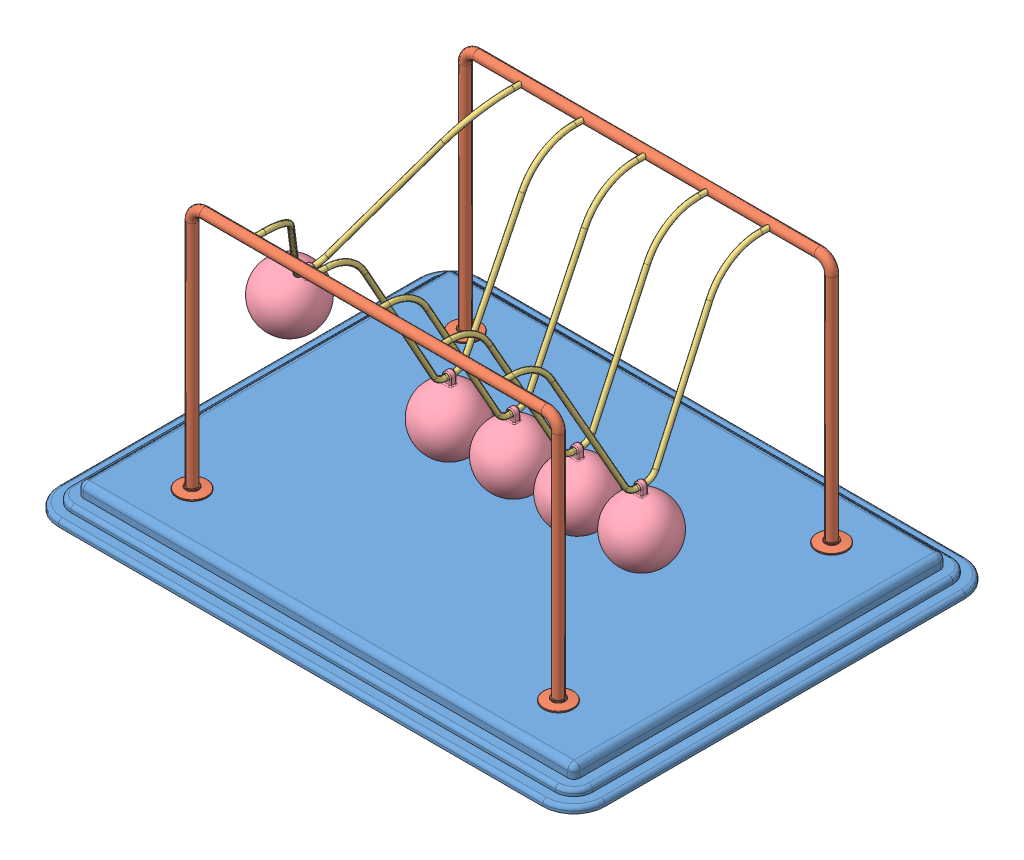
SolidWorks assembly Newtons Cradle NewtonsCradle 0250, configuration Default. Lengths in mm.
Overall size (440 222 340).
13 component instances, 4 part files, 34 mates.
Components (placement in the parent):
- Base 202.59319286872-1: Base 202.59319286872 [Default] at (-16.2968 -4.1587 11.425) size (440 20 340)
- frame NewtonsCradle 0250-1: frame NewtonsCradle 0250 [Default] at (-16.2968 144.4547 -98.575) size (319 202 24)
- frame NewtonsCradle 0250-2: frame NewtonsCradle 0250 [Default] at (-16.2968 144.4547 121.425) x (-1 0 0) z (0 0 -1) size (319 202 24)
- Hanging thing NewtonsCradle 0250-1: Hanging thing NewtonsCradle 0250 [Default] at (-157.6326 134.1825 11.425) x (0 0 1) z (-0.859985 0.510319 0) size (220 129 4)
- Hanging thing NewtonsCradle 0250-2: Hanging thing NewtonsCradle 0250 [Default] at (-66.576 122.8418 11.425) x (0 0 1) z (-0.999994 0.003446 0) size (220 129 4)
- Hanging thing NewtonsCradle 0250-3: Hanging thing NewtonsCradle 0250 [Default] at (-15.6923 122.8436 11.425) x (0 0 1) z (-0.999972 -0.007464 0) size (220 129 4)
- Hanging thing NewtonsCradle 0250-4: Hanging thing NewtonsCradle 0250 [Default] at (35.2213 122.8555 11.425) x (0 0 1) z (-0.999824 -0.018742 0) size (220 129 4)
- Hanging thing NewtonsCradle 0250-5: Hanging thing NewtonsCradle 0250 [Default] at (86.0287 122.8747 11.425) x (0 0 1) z (-0.999588 -0.028711 0) size (220 129 4)
- Sphere NewtonsCradle 0250-1: Sphere NewtonsCradle 0250 [Default] at (-195.3962 70.5436 11.425) x (0.859985 -0.510319 0) z (0 0 1) size (50 58.5 50)
- Sphere NewtonsCradle 0250-2: Sphere NewtonsCradle 0250 [Default] at (88.1533 48.9052 11.425) x (0.999588 0.028711 0) z (0 0 1) size (50 58.5 50)
- Sphere NewtonsCradle 0250-3: Sphere NewtonsCradle 0250 [Default] at (-15.14 48.8456 11.425) x (0.999972 0.007464 0) z (0 0 1) size (50 58.5 50)
- Sphere NewtonsCradle 0250-4: Sphere NewtonsCradle 0250 [Default] at (36.6081 48.8685 11.425) x (0.999824 0.018742 0) z (0 0 1) size (50 58.5 50)
- Sphere NewtonsCradle 0250-5: Sphere NewtonsCradle 0250 [Default] at (-66.831 48.8422 11.425) x (0.999994 -0.003446 0) z (0 0 1) size (50 58.5 50)
Mates (geometry in assembly coordinates):
- Coincident1: coincident anti-aligned: plane of Base-1 through (-211.2968 5.8413 156.425) normal (0 1 0); plane of frame-2 through (-175.7968 5.8413 121.425) normal (0 -1 0)
- Coincident2: coincident anti-aligned: plane of Base-1 through (-211.2968 5.8413 156.425) normal (0 1 0); plane of frame-1 through (143.2032 5.8413 -98.575) normal (0 -1 0)
- Concentric1: concentric anti-aligned: cylinder of frame-1 through (-116.2968 203.8413 -94.575) axis (0 0 -1) radius 2; cylinder of frame-2 through (-116.2968 203.8413 117.425) axis (0 0 1) radius 2
- Concentric2: concentric anti-aligned: cylinder of frame-1 through (83.7032 203.8413 -94.575) axis (0 0 -1) radius 2; cylinder of frame-2 through (83.7032 203.8413 117.425) axis (0 0 1) radius 2
- Distance1: distance = 60 mm: plane of frame-1 through (-16.2968 144.4547 -98.575) normal (0 0 1); line of Base-1 through (-211.2968 -12.1587 -158.575) axis (1 0 0)
- Distance2: distance = 60 mm: line of Base-1 through (178.7032 -12.1587 181.425) axis (-1 0 0); plane of frame-2 through (-16.2968 144.4547 121.425) normal (0 0 -1)
- Distance3: distance = 220 mm: plane of frame-2 through (-16.2968 144.4547 121.425) normal (-1 0 0); line of Base-1 through (-236.2968 -12.1587 156.425) axis (0 0 -1)
- Concentric3: concentric anti-aligned: cylinder of frame-1 through (-116.2968 203.8413 -94.575) axis (0 0 -1) radius 2; cylinder of Hanging thing-1 through (-116.2968 203.8413 111.425) axis (0 0 1) radius 2
- Concentric4: concentric anti-aligned: cylinder of frame-1 through (-116.2968 203.8413 -94.575) axis (0 0 -1) radius 2; cylinder of Hanging thing-1 through (-116.2968 203.8413 -98.575) axis (0 0 1) radius 2
- Concentric5: concentric aligned: cylinder of frame-2 through (-66.2968 203.8413 117.425) axis (0 0 1) radius 2; cylinder of Hanging thing-2 through (-66.2968 203.8413 111.425) axis (0 0 1) radius 2
- Concentric6: concentric aligned: cylinder of frame-2 through (-16.2968 203.8413 117.425) axis (0 0 1) radius 2; cylinder of Hanging thing-3 through (-16.2968 203.8413 111.425) axis (0 0 1) radius 2
- Concentric7: concentric aligned: cylinder of frame-2 through (33.7032 203.8413 117.425) axis (0 0 1) radius 2; cylinder of Hanging thing-4 through (33.7032 203.8413 111.425) axis (0 0 1) radius 2
- Concentric8: concentric aligned: cylinder of frame-2 through (83.7032 203.8413 117.425) axis (0 0 1) radius 2; cylinder of Hanging thing-5 through (83.7032 203.8413 111.425) axis (0 0 1) radius 2
- Coincident5: coincident anti-aligned: plane of frame-2 through (83.7032 203.8413 121.425) normal (0 0 -1); plane of Hanging thing-5 through (83.7032 203.8413 121.425) normal (0 0 1)
- Coincident6: coincident anti-aligned: plane of frame-2 through (33.7032 203.8413 121.425) normal (0 0 -1); plane of Hanging thing-4 through (33.7032 203.8413 121.425) normal (0 0 1)
- Coincident7: coincident anti-aligned: plane of frame-2 through (-16.2968 203.8413 121.425) normal (0 0 -1); plane of Hanging thing-3 through (-16.2968 203.8413 121.425) normal (0 0 1)
- Coincident8: coincident anti-aligned: plane of frame-2 through (-66.2968 203.8413 121.425) normal (0 0 -1); plane of Hanging thing-2 through (-66.2968 203.8413 121.425) normal (0 0 1)
- Coincident9: coincident anti-aligned: plane of frame-2 through (-116.2968 203.8413 121.425) normal (0 0 -1); plane of Hanging thing-1 through (-116.2968 203.8413 121.425) normal (0 0 1)
- Concentric9: concentric anti-aligned: cylinder of Hanging thing-1 through (-117.0163 78.8434 7.925) axis (0 0 1) radius 2; cylinder of Sphere-1 through (-117.0163 78.8434 13.925) axis (0 0 -1) radius 2
- Concentric13: concentric anti-aligned: cylinder of Hanging thing-2 through (-66.7276 78.842 7.925) axis (0 0 1) radius 2; cylinder of Sphere-5 through (-66.7276 78.842 13.925) axis (0 0 -1) radius 2
- Concentric15: concentric anti-aligned: cylinder of Hanging thing-3 through (-15.3639 78.8448 7.925) axis (0 0 1) radius 2; cylinder of Sphere-3 through (-15.3639 78.8448 13.925) axis (0 0 -1) radius 2
- Concentric16: concentric anti-aligned: cylinder of Hanging thing-5 through (87.292 78.8928 7.925) axis (0 0 1) radius 2; cylinder of Sphere-2 through (87.292 78.8928 13.925) axis (0 0 -1) radius 2
- Concentric17: concentric anti-aligned: cylinder of Hanging thing-4 through (36.0459 78.8632 7.925) axis (0 0 1) radius 2; cylinder of Sphere-4 through (36.0459 78.8632 13.925) axis (0 0 -1) radius 2
- Parallel1: parallel anti-aligned: plane of Hanging thing-1; plane of Sphere-1
- Coincident22: coincident anti-aligned: plane of Hanging thing-1; plane of Sphere-1
- Coincident12: coincident aligned: plane of Hanging thing-2 through (-66.576 122.8418 11.425) normal (0 0 1); plane of Sphere-5 through (-66.831 48.8422 11.425) normal (0 0 1)
- Coincident10: coincident aligned: plane of Hanging thing-1 through (-116.763 122.8426 11.425) normal (0 0 1); plane of Sphere-1 through (-118.5806 48.8842 11.425) normal (0 0 1)
- Coincident13: coincident anti-aligned: plane of Hanging thing-2 through (-66.576 122.8418 11.425) normal (-0.999994 0.003446 0); plane of Sphere-5 through (-66.831 48.8422 11.425) normal (0.999994 -0.003446 0)
- Coincident14: coincident anti-aligned: plane of Hanging thing-3 through (-15.6923 122.8436 11.425) normal (-0.999972 -0.007464 0); plane of Sphere-3 through (-15.14 48.8456 11.425) normal (0.999972 0.007464 0)
- Coincident15: coincident aligned: plane of Hanging thing-3 through (-15.6923 122.8436 11.425) normal (0 0 1); plane of Sphere-3 through (-15.14 48.8456 11.425) normal (0 0 1)
- Coincident18: coincident aligned: plane of Hanging thing-4 through (35.2213 122.8555 11.425) normal (0 0 1); plane of Sphere-4 through (36.6081 48.8685 11.425) normal (0 0 1)
- Coincident19: coincident anti-aligned: plane of Hanging thing-4 through (35.2213 122.8555 11.425) normal (-0.999824 -0.018742 0); plane of Sphere-4 through (36.6081 48.8685 11.425) normal (0.999824 0.018742 0)
- Coincident20: coincident anti-aligned: plane of Hanging thing-5 through (86.0287 122.8747 11.425) normal (-0.999588 -0.028711 0); plane of Sphere-2 through (88.1533 48.9052 11.425) normal (0.999588 0.028711 0)
- Coincident21: coincident aligned: plane of Hanging thing-5 through (86.0287 122.8747 11.425) normal (0 0 1); plane of Sphere-2 through (88.1533 48.9052 11.425) normal (0 0 1)
